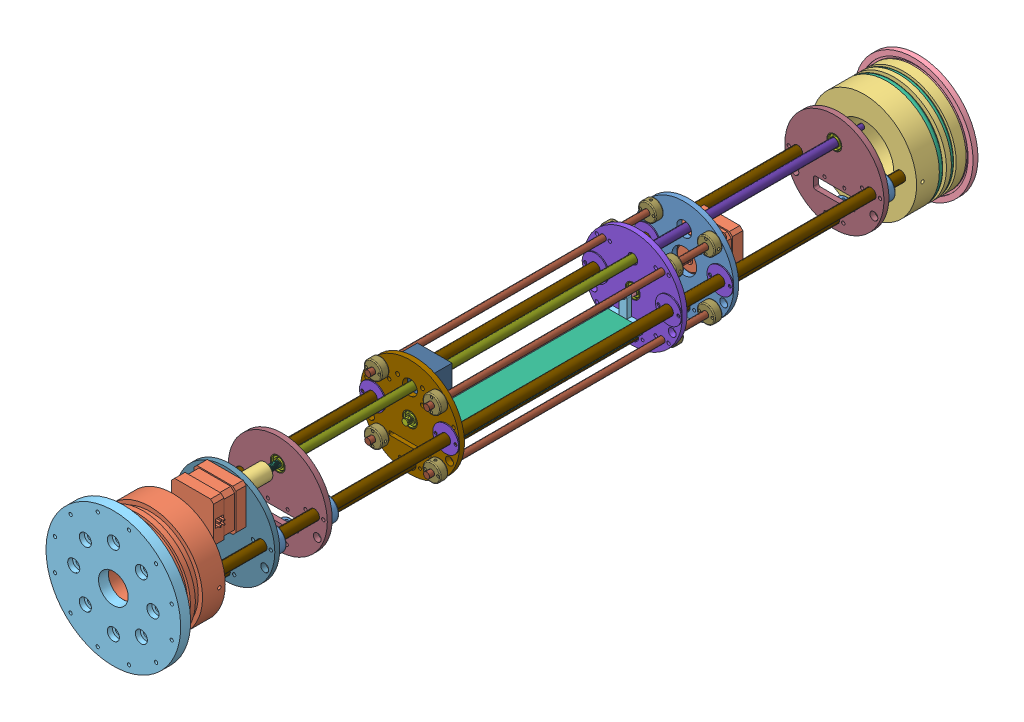
SolidWorks assembly MM_Main, configuration Default. Lengths in mm.
Overall size (192.33 192.33 813).
66 component instances, 27 part files, 135 mates.
Components (placement in the parent):
- MM_moving_stepper_disk-1: MM_moving_stepper_disk [Default] at (0 0 -581.4) size (100 100 5)
- MM_NEMA_17-1: MM_NEMA_17 [Default] at (0 -2 -614.4) x (1 0 0) z (0 -1 0) size (45.3 55 42.3)
- MM_5x5coupler-1: MM_5x5coupler [Default] at (0 -2 -541.4) x (0.507474 0.861667 0) z (0 0 -1) size (16 16 26)
- MM_Mass_shaft2-1: MM_Mass_shaft2 [Default] at (0 -2 -549.4) x (0.265176 0.9642 0) z (0.9642 -0.265176 0) size (8 34 8)
- MM_Mass_handle-1: MM_Mass_handle [Default] at (0 -30 -519.4) size (30 32 5)
- MM_Mass-1: MM_Mass [Default] at (-15 -30 -519.4) size (30 10 200)
- MM_Mass_handle-2: MM_Mass_handle [Default] at (0 -30 -314.4) size (30 32 5)
- MM_Mass_shaft-2: MM_Mass_shaft [Default] at (0 -2 -309.4) x (-0.93094 -0.365173 0) z (-0.365173 0.93094 0) size (9.17 19 8.51)
- MM_moving_disk-1: MM_moving_disk [Default] at (0 0 -529.4) size (100 100 5)
- MM_moving_disk2-1: MM_moving_disk2 [Default] at (0 0 -304.5) size (100 100 5)
- MM_shft_screw_nut-1: MM_shft_screw_nut [Default] at (0 26 -304.5) x (-1 0 0) z (0 -1 0) size (35 20 30)
- MM_moving_construct-1: MM_moving_construct [Default] at (-29.6985 29.6985 -586.5) x (-0.109158 -0.994024 0) z (0 0 1) size (6 6 300)
- MM_moving_construct-2: MM_moving_construct [Default] at (-29.6985 -29.6985 -586.5) x (0.994024 -0.109158 0) z (0 0 1) size (6 6 300)
- MM_moving_construct-3: MM_moving_construct [Default] at (29.6985 -29.6985 -586.5) x (0.109158 0.994024 0) z (0 0 1) size (6 6 300)
- MM_moving_construct-4: MM_moving_construct [Default] at (29.6985 29.6985 -586.5) x (-0.994024 0.109158 0) z (0 0 1) size (6 6 300)
- MM_moving_fix_thread-1: MM_moving_fix_thread [Default] at (29.6985 29.6985 -576.4) x (0 -1 0) z (0 0 1) size (18 18 8)
- MM_moving_fix_thread-2: MM_moving_fix_thread [Default] at (29.6985 29.6985 -537.4) x (0 -1 0) z (0 0 1) size (18 18 8)
- MM_moving_fix_thread-3: MM_moving_fix_thread [Default] at (29.6985 29.6985 -299.5) x (0 1 0) z (0 0 1) size (18 18 8)
- MM_moving_fix_thread-4: MM_moving_fix_thread [Default] at (29.6985 -29.6985 -576.4) x (-1 0 0) z (0 0 1) size (18 18 8)
- MM_moving_fix_thread-5: MM_moving_fix_thread [Default] at (-29.6985 -29.6985 -576.4) x (0 1 0) z (0 0 1) size (18 18 8)
- MM_moving_fix_thread-6: MM_moving_fix_thread [Default] at (-29.6985 29.6985 -576.4) size (18 18 8)
- MM_moving_fix_thread-7: MM_moving_fix_thread [Default] at (29.6985 -29.6985 -537.4) x (-1 0 0) z (0 0 1) size (18 18 8)
- MM_moving_fix_thread-8: MM_moving_fix_thread [Default] at (-29.6985 -29.6985 -537.4) x (0 1 0) z (0 0 1) size (18 18 8)
- MM_moving_fix_thread-9: MM_moving_fix_thread [Default] at (-29.6985 29.6985 -537.4) size (18 18 8)
- MM_moving_fix_thread-10: MM_moving_fix_thread [Default] at (29.6985 -29.6985 -299.5) size (18 18 8)
- MM_moving_fix_thread-11: MM_moving_fix_thread [Default] at (-29.6985 -29.6985 -299.5) x (0 -1 0) z (0 0 1) size (18 18 8)
- MM_moving_fix_thread-12: MM_moving_fix_thread [Default] at (-29.6985 29.6985 -299.5) x (-1 0 0) z (0 0 1) size (18 18 8)
- MM_static2.2-1: MM_static2.2 [Default] at (0 0 -171) size (100 100 5)
- MM_static_stepper-1: MM_static_stepper [Default] at (0 0 -118) size (100 100 5)
- MM_NEMA_17-2: MM_NEMA_17 [Default] at (0 26 -80) x (-1 0 0) z (0 -1 0) size (45.3 55 42.3)
- MM_5x5coupler-2: MM_5x5coupler [Default] at (0 26 -153) x (-0.062572 0.99804 0) z (0 0 1) size (16 16 26)
- MM_shaft_extend-2: MM_shaft_extend [Default] at (0 26 -145) x (-0.999277 -0.038026 0) z (0 0 -1) size (8 8 41)
- MM_shaft-2: MM_shaft [Default] at (0 26 -536) x (0.038026 -0.999277 0) z (0 0 1) size (8 8 360)
- MM_shaft_extend_long -1: MM_shaft_extend_long  [Default] at (0 26 -756) x (0.999277 0.038026 0) z (0 0 1) size (8 8 230)
- MM_static2.2-2: MM_static2.2 [Default] at (0 0 -733) size (100 100 5)
- MM_construct-1: MM_construct [Default] at (-37 0 -775.5) x (0.04747 0.998873 0) z (0 0 1) size (10 10 733)
- MM_fix-1: MM_fix [Default] at (-37 0 -179) x (0.99297 0.118365 0) z (0 0 1) size (24 24 8)
- MM_fix-2: MM_fix [Default] at (-37 0 -126) size (24 24 8)
- MM_fix-3: MM_fix [Default] at (-37 0 -741) size (24 24 8)
- MM_fix-4: MM_fix [Default] at (37 0 -733) x (-1 0 0) z (0 0 -1) size (24 24 8)
- MM_construct-2: MM_construct [Default] at (37 0 -42.5) x (-0.04747 0.998873 0) z (0 0 -1) size (10 10 733)
- MM_fix-5: MM_fix [Default] at (37 0 -171) x (-0.99297 0.118365 0) z (0 0 -1) size (24 24 8)
- MM_fix-6: MM_fix [Default] at (37 0 -118) x (-1 0 0) z (0 0 -1) size (24 24 8)
- MM_construct-3: MM_construct [Default] at (0 -40 -775.5) x (0.99877 -0.049577 0) z (0 0 1) size (10 10 733)
- MM_fix-7: MM_fix [Default] at (0 -40 -179) x (0.999988 0.004807 0) z (0 0 1) size (24 24 8)
- MM_fix-8: MM_fix [Default] at (0 -40 -126) x (0.999988 0.004807 0) z (0 0 1) size (24 24 8)
- MM_fix-9: MM_fix [Default] at (0 -40 -741) x (0.999988 0.004807 0) z (0 0 1) size (24 24 8)
- SE_mid_flange -1: SE_mid_flange  [Default] at (0 0 -10) x (-1 0 0) z (0 0 -1) size (106 106 50)
- SE_end_flange  - Copy-1: SE_end_flange  - Copy [Default] at (0 0 -808) size (106 106 50)
- SE_head3-1: SE_head3 [Default] at (0 0 -813) size (120 120 5)
- SE_cylinder-1: SE_cylinder [Default] at (0 0 -808) size (110.4 110.4 798) (hidden)
- SE_head2.2-1: SE_head2.2 [Default] at (0 0 -10) x (0.707107 -0.707107 0) z (0 0 1) size (136 136 10)
- o-rings ai-1: o-rings ai [AS568 - 241] at (0 0 -794.9393) x (1 0 0) z (0 -1 0) size (105.08 3.53 105.08)
- o-rings ai-2: o-rings ai [AS568 - 343] at (0 0 -783.6274) x (1 0 0) z (0 1 0) size (105.28 5.33 105.28)
- o-rings ai-3: o-rings ai [AS568 - 224] at (0 0 -807.0983) x (-1 0 0) z (0 -1 0) size (51.1 3.53 51.1)
- o-rings ai-7: o-rings ai [AS568 - 045] at (0 0 -808.5588) x (1 0 0) z (0 1 0) size (104.37 1.52 104.37)
- angular contact ball bearing_68_iso-1: angular contact ball bearing_68_iso [ISO 15 ABB - 196 - 10,SI,NC,10_68] at (0 -2 -302) x (0 0 -1) z (1 0 0) size (5 15 15)
- angular contact ball bearing_68_iso-2: angular contact ball bearing_68_iso [ISO 15 ABB - 196 - 10,SI,NC,10_68] at (0 26 -168.5) x (0 0 -1) z (1 0 0) size (5 15 15)
- angular contact ball bearing_68_iso-3: angular contact ball bearing_68_iso [ISO 15 ABB - 196 - 10,SI,NC,10_68] at (0 26 -730.5) x (0 0 -1) z (1 0 0) size (5 15 15)
- angular contact ball bearing_68_iso-4: angular contact ball bearing_68_iso [ISO 15 ABB - 196 - 10,SI,NC,10_68] at (0 -2 -526.9) x (0 0 -1) z (1 0 0) size (5 15 15)
- MM_smooth-1: MM_smooth [Default] at (-37 0 -581.4) size (26 26 6)
- MM_smooth-2: MM_smooth [Default] at (37 0 -581.4) size (26 26 6)
- MM_smooth-4: MM_smooth [Default] at (37 0 -529.4) size (26 26 6)
- MM_smooth-6: MM_smooth [Default] at (-37 0 -529.4) size (26 26 6)
- MM_smooth-8: MM_smooth [Default] at (37 0 -304.5) size (26 26 6)
- MM_smooth-9: MM_smooth [Default] at (-37 0 -304.5) size (26 26 6)
Mates (geometry in assembly coordinates):
- Concentric1: concentric anti-aligned: cylinder of MM_moving_stepper_disk-1 through (0 -2 -586.4) axis (0 0 1) radius 12.5; cylinder of MM_NEMA_17-1 through (0 -2 -559.4) axis (0 0 -1) radius 2.5
- Concentric2: concentric aligned: cylinder of MM_moving_stepper_disk-1 through (15.5 13.5 -586.4) axis (0 0 1) radius 2; cylinder of MM_NEMA_17-1 through (15.5 13.5 -585.9) axis (0 0 1) radius 1.5
- Coincident1: coincident anti-aligned: plane of MM_moving_stepper_disk-1 through (0 0 -581.4) normal (0 0 -1); plane of MM_NEMA_17-1 through (0 -2 -581.4) normal (0 0 1)
- Concentric3: concentric anti-aligned: cylinder of MM_NEMA_17-1 through (0 -2 -559.4) axis (0 0 -1) radius 2.5; cylinder of MM_5x5coupler-1 through (0 -2 -567.4) axis (0 0 1) radius 2.5
- Coincident3: coincident anti-aligned: plane of MM_NEMA_17-1 through (0 -2 -559.4) normal (0 0 1); circle of MM_5x5coupler-1
- Concentric7: concentric anti-aligned: cylinder of MM_5x5coupler-1 through (0 -2 -567.4) axis (0 0 1) radius 2.5; cylinder of MM_Mass_shaft2-1 through (0 -2 -534.4) axis (0 0 -1) radius 2.5
- Coincident5: coincident aligned: circle of MM_5x5coupler-1; plane of MM_Mass_shaft2-1 through (0 -2 -549.4) normal (0 0 -1)
- Concentric9: concentric aligned: cylinder of MM_Mass_shaft2-1 through (0 -2 -519.4) axis (0 0 -1) radius 4; cylinder of MM_Mass_handle-1 through (0 -2 -514.4) axis (0 0 -1) radius 4
- Coincident7: coincident anti-aligned: plane of MM_Mass_shaft2-1 through (0 -2 -519.4) normal (0 0 1); plane of MM_Mass_handle-1 through (0 -2 -519.4) normal (0 0 -1)
- Coincident8: coincident anti-aligned: plane of MM_Mass_handle-1 through (0 -2 -514.4) normal (0 0 1); plane of MM_Mass-1 through (15 -30 -514.4) normal (0 0 -1)
- Coincident9: coincident aligned: plane of MM_Mass_handle-1 through (-15 -30 -514.4) normal (-1 0 0); plane of MM_Mass-1 through (-15 -30 -309.4) normal (-1 0 0)
- Coincident10: coincident aligned: plane of MM_Mass_handle-1 through (15 -30 -514.4) normal (0 -1 0); plane of MM_Mass-1 through (-15 -30 -309.4) normal (0 -1 0)
- Coincident11: coincident aligned: plane of MM_Mass-1 through (15 -30 -309.4) normal (1 0 0); plane of MM_Mass_handle-2 through (15 -20 -309.4) normal (1 0 0)
- Coincident12: coincident anti-aligned: plane of MM_Mass-1 through (15 -30 -314.4) normal (0 0 1); plane of MM_Mass_handle-2 through (0 -2 -314.4) normal (0 0 -1)
- Coincident13: coincident aligned: plane of MM_Mass-1 through (-15 -30 -309.4) normal (0 -1 0); plane of MM_Mass_handle-2 through (15 -30 -309.4) normal (0 -1 0)
- Concentric10: concentric aligned: cylinder of MM_Mass_handle-2 through (0 -2 -309.4) axis (0 0 -1) radius 4; cylinder of MM_Mass_shaft-2 through (0 -2 -294.4) axis (0 0 -1) radius 4
- Coincident14: coincident anti-aligned: plane of MM_Mass_handle-2 through (0 -2 -309.4) normal (0 0 1); plane of MM_Mass_shaft-2 through (0 -2 -309.4) normal (0 0 -1)
- Concentric11: concentric aligned: cylinder of MM_moving_stepper_disk-1 through (0 0 -576.4) axis (0 0 -1) radius 50; cylinder of MM_moving_disk-1 through (0 0 -524.4) axis (0 0 -1) radius 50
- Concentric12: concentric aligned: cylinder of MM_moving_stepper_disk-1 through (37 0 -581.4) axis (0 0 -1) radius 7; cylinder of MM_moving_disk-1 through (37 0 -529.4) axis (0 0 -1) radius 7
- Coincident15: coincident anti-aligned: plane of MM_Mass_shaft2-1 through (0 -2 -524.4) normal (0 0 -1); plane of MM_moving_disk-1 through (0 0 -524.4) normal (0 0 1)
- Concentric13: concentric aligned: cylinder of MM_moving_disk-1 through (0 0 -524.4) axis (0 0 -1) radius 50; cylinder of MM_moving_disk2-1 through (0 0 -299.5) axis (0 0 -1) radius 50
- Concentric14: concentric aligned: cylinder of MM_moving_disk-1 through (37 0 -529.4) axis (0 0 -1) radius 7; cylinder of MM_moving_disk2-1 through (37 0 -304.5) axis (0 0 -1) radius 7
- Coincident16: coincident anti-aligned: plane of MM_Mass_shaft-2 through (0 -2 -304.5) normal (0 0 1); plane of MM_moving_disk2-1 through (0 0 -304.5) normal (0 0 -1)
- Concentric15: concentric aligned: cylinder of MM_moving_disk2-1 through (0 26 -309.5) axis (0 0 1) radius 7.5; cylinder of MM_shft_screw_nut-1 through (0 26 -324.5) axis (0 0 1) radius 8.5
- Concentric16: concentric aligned: cylinder of MM_moving_disk2-1 through (12.5 31.5 -309.5) axis (0 0 1) radius 2; cylinder of MM_shft_screw_nut-1 through (12.5 31.5 -304.5) axis (0 0 1) radius 1.25
- Coincident17: coincident anti-aligned: plane of MM_moving_disk2-1 through (0 0 -304.5) normal (0 0 -1); plane of MM_shft_screw_nut-1 through (0 26 -304.5) normal (0 0 1)
- Concentric17: concentric anti-aligned: cylinder of MM_moving_disk2-1 through (-29.6985 29.6985 -309.5) axis (0 0 1) radius 3; cylinder of MM_moving_construct-1 through (-29.6985 29.6985 -286.5) axis (0 0 -1) radius 3
- Coincident27: coincident anti-aligned: circle of MM_moving_stepper_disk-1; cylinder of MM_moving_fix_thread-1 through (29.6985 29.6985 -576.4) axis (0 0 -1) radius 3
- Coincident28: coincident anti-aligned: plane of MM_moving_stepper_disk-1 through (0 0 -576.4) normal (0 0 1); plane of MM_moving_fix_thread-1 through (29.6985 29.6985 -576.4) normal (0 0 -1)
- Coincident30: coincident anti-aligned: circle of MM_moving_disk-1; cylinder of MM_moving_fix_thread-2 through (29.6985 29.6985 -537.4) axis (0 0 -1) radius 3
- Coincident31: coincident anti-aligned: plane of MM_moving_fix_thread-2 through (29.6985 29.6985 -529.4) normal (0 0 1); plane of MM_moving_disk-1 through (0 0 -529.4) normal (0 0 -1)
- Coincident33: coincident anti-aligned: circle of MM_moving_disk2-1; cylinder of MM_moving_fix_thread-3 through (29.6985 29.6985 -299.5) axis (0 0 -1) radius 3
- Coincident34: coincident anti-aligned: plane of MM_moving_disk2-1 through (0 0 -299.5) normal (0 0 1); plane of MM_moving_fix_thread-3 through (29.6985 29.6985 -299.5) normal (0 0 -1)
- Concentric18: concentric aligned: cylinder of MM_moving_disk2-1 through (0 0 -299.5) axis (0 0 -1) radius 50; cylinder of MM_static2.2-1 through (0 0 -166) axis (0 0 -1) radius 50
- Concentric19: concentric aligned: cylinder of MM_moving_disk2-1 through (-37 0 -304.5) axis (0 0 -1) radius 7; cylinder of MM_static2.2-1 through (-37 0 -171) axis (0 0 -1) radius 5.1
- Concentric20: concentric aligned: cylinder of MM_static2.2-1 through (0 0 -166) axis (0 0 -1) radius 50; cylinder of MM_static_stepper-1 through (0 0 -113) axis (0 0 -1) radius 50
- Concentric21: concentric aligned: cylinder of MM_static2.2-1 through (0 26 -176) axis (0 0 1) radius 7.5; cylinder of MM_static_stepper-1 through (0 26 -123) axis (0 0 1) radius 12.5
- Concentric22: concentric aligned: cylinder of MM_static_stepper-1 through (0 26 -123) axis (0 0 1) radius 12.5; cylinder of MM_NEMA_17-2 through (0 26 -135) axis (0 0 1) radius 2.5
- Parallel6: parallel aligned: plane of MM_NEMA_17-2 through (-16 46 -90.5) normal (0 1 0); plane of assembly through (0 0 0) normal (0 1 0)
- Coincident37: coincident anti-aligned: plane of MM_static_stepper-1 through (0 0 -113) normal (0 0 1); plane of MM_NEMA_17-2 through (0 26 -113) normal (0 0 -1)
- Coincident38: coincident anti-aligned: plane of MM_NEMA_17-2 through (0 26 -135) normal (0 0 -1); circle of MM_5x5coupler-2
- Concentric23: concentric anti-aligned: cylinder of MM_NEMA_17-2 through (0 26 -135) axis (0 0 1) radius 2.5; cylinder of MM_5x5coupler-2 through (0 26 -127) axis (0 0 -1) radius 2.5
- Coincident39: coincident aligned: circle of MM_5x5coupler-2; plane of MM_shaft_extend-2 through (0 26 -145) normal (0 0 1)
- Concentric24: concentric anti-aligned: cylinder of MM_5x5coupler-2 through (0 26 -127) axis (0 0 -1) radius 2.5; cylinder of MM_shaft_extend-2 through (0 26 -155) axis (0 0 1) radius 2.5
- Coincident40: coincident anti-aligned: plane of MM_static2.2-1 through (0 0 -171) normal (0 0 -1); plane of MM_shaft_extend-2 through (0 26 -171) normal (0 0 1)
- Concentric25: concentric anti-aligned: cylinder of MM_shft_screw_nut-1 through (0 26 -324.5) axis (0 0 1) radius 8.5; cylinder of MM_shaft-2 through (0 26 -186) axis (0 0 -1) radius 4
- Coincident41: coincident anti-aligned: plane of MM_shaft_extend-2 through (0 26 -176) normal (0 0 -1); plane of MM_shaft-2 through (0 26 -176) normal (0 0 1)
- Concentric26: concentric anti-aligned: cylinder of MM_shaft_extend-2 through (-9.9928 25.6197 -181) axis (0.999277 0.038026 0) radius 1; cylinder of MM_shaft-2 through (2.9978 26.1141 -181) axis (-0.999277 -0.038026 0) radius 1
- Distance1: distance = 5 mm aligned: plane of MM_moving_construct-3 through (29.6985 -29.6985 -286.5) normal (0 0 1); plane of MM_moving_fix_thread-10 through (29.6985 -29.6985 -291.5) normal (0 0 1)
- Concentric27: concentric anti-aligned: cylinder of MM_shaft-2 through (0 26 -526) axis (0 0 -1) radius 3; cylinder of MM_shaft_extend_long -1 through (0 26 -536) axis (0 0 1) radius 3
- Concentric28: concentric anti-aligned: cylinder of MM_shaft-2 through (-3.9971 25.8479 -531) axis (0.999277 0.038026 0) radius 1; cylinder of MM_shaft_extend_long -1 through (9.9928 26.3803 -531) axis (-0.999277 -0.038026 0) radius 1
- Concentric29: concentric aligned: cylinder of MM_static2.2-1 through (0 0 -166) axis (0 0 -1) radius 50; cylinder of MM_static2.2-2 through (0 0 -728) axis (0 0 -1) radius 50
- Concentric30: concentric anti-aligned: cylinder of MM_shaft_extend_long -1 through (0 26 -526) axis (0 0 -1) radius 4; cylinder of MM_static2.2-2 through (0 26 -738) axis (0 0 1) radius 7.5
- Coincident44: coincident anti-aligned: plane of MM_shaft_extend_long -1 through (0 26 -728) normal (0 0 -1); plane of MM_static2.2-2 through (0 0 -728) normal (0 0 1)
- LimitDistance1: limit distance = 128.5 mm anti-aligned: plane of MM_moving_disk2-1 through (0 0 -299.5) normal (0 0 1); plane of MM_static2.2-1 through (0 0 -171) normal (0 0 -1)
- Concentric31: concentric aligned: cylinder of MM_static_stepper-1 through (-37 0 -118) axis (0 0 -1) radius 5.1; cylinder of MM_construct-1 through (-37 0 -42.5) axis (0 0 -1) radius 5
- Concentric32: concentric aligned: cylinder of MM_fix-1 through (-37 0 -179) axis (0 0 -1) radius 5.1; circle of MM_static2.2-1
- Coincident47: coincident anti-aligned: plane of MM_static2.2-1 through (0 0 -171) normal (0 0 -1); plane of MM_fix-1 through (-37 0 -171) normal (0 0 1)
- Coincident52: coincident aligned: circle of MM_static_stepper-1; cylinder of MM_fix-2 through (-37 0 -126) axis (0 0 -1) radius 5.1
- Coincident53: coincident anti-aligned: plane of MM_static_stepper-1 through (0 0 -118) normal (0 0 -1); plane of MM_fix-2 through (-37 0 -118) normal (0 0 1)
- Coincident59: coincident aligned: circle of MM_static2.2-2; cylinder of MM_fix-3 through (-37 0 -741) axis (0 0 -1) radius 5.1
- Coincident60: coincident anti-aligned: plane of MM_static2.2-2 through (0 0 -733) normal (0 0 -1); plane of MM_fix-3 through (-37 0 -733) normal (0 0 1)
- Coincident77: coincident anti-aligned: plane of MM_static_stepper-1 through (0 0 -118) normal (0 0 -1); plane of MM_fix-8 through (0 -40 -118) normal (0 0 1)
- Coincident79: coincident anti-aligned: plane of MM_static2.2-1 through (0 0 -171) normal (0 0 -1); plane of MM_fix-7 through (0 -40 -171) normal (0 0 1)
- Coincident81: coincident anti-aligned: plane of MM_static2.2-2 through (0 0 -733) normal (0 0 -1); plane of MM_fix-9 through (0 -40 -733) normal (0 0 1)
- Concentric40: concentric aligned: cylinder of MM_construct-3 through (0 -40 -42.5) axis (0 0 -1) radius 5; cylinder of MM_fix-9 through (0 -40 -741) axis (0 0 -1) radius 5.1
- Coincident82: coincident aligned: plane of MM_construct-1 through (-37 0 -775.5) normal (0 0 -1); plane of MM_construct-3 through (0 -40 -775.5) normal (0 0 -1)
- Concentric41: concentric anti-aligned: cylinder of MM_static_stepper-1 through (0 0 -113) axis (0 0 -1) radius 50; cylinder of SE_mid_flange -1 through (0 0 -60) axis (0 0 1) radius 53
- Distance2: distance = 20 mm anti-aligned: plane of SE_mid_flange -1 through (0 0 -60) normal (0 0 -1); plane of MM_NEMA_17-2 through (0 26 -80) normal (0 0 1)
- Coincident84: coincident anti-aligned: plane of MM_construct-1 through (-37 0 -42.5) normal (0 0 1); circle of SE_mid_flange -1
- Concentric46: concentric aligned: cylinder of MM_static2.2-2 through (0 0 -728) axis (0 0 -1) radius 50; cylinder of SE_end_flange  - Copy-1 through (0 0 -758) axis (0 0 -1) radius 53
- Concentric47: concentric anti-aligned: circle of MM_fix-3; cylinder of SE_end_flange  - Copy-1 through (-37 0 -758) axis (0 0 1) radius 5
- Concentric48: concentric anti-aligned: cylinder of SE_end_flange  - Copy-1 through (0 0 -758) axis (0 0 -1) radius 53; cylinder of SE_head3-1 through (0 0 -813) axis (0 0 1) radius 60
- Concentric49: concentric anti-aligned: cylinder of SE_end_flange  - Copy-1 through (-28.2843 28.2843 -808) axis (0 0 -1) radius 2.1; cylinder of SE_head3-1 through (-28.2843 28.2843 -813) axis (0 0 1) radius 3
- Coincident88: coincident anti-aligned: plane of SE_end_flange  - Copy-1 through (0 0 -808) normal (0 0 -1); plane of SE_head3-1 through (0 0 -808) normal (0 0 1)
- Concentric50: concentric aligned: cylinder of SE_end_flange  - Copy-1 through (0 0 -758) axis (0 0 -1) radius 53; cylinder of SE_cylinder-1 through (0 0 -10) axis (0 0 -1) radius 53
- Coincident89: coincident anti-aligned: plane of SE_head3-1 through (0 0 -808) normal (0 0 1); plane of SE_cylinder-1 through (0 0 -808) normal (0 0 -1)
- Coincident92: coincident aligned: plane of SE_cylinder-1 through (0 0 -808) normal (1 0 0); plane of assembly through (0 0 0) normal (1 0 0)
- Coincident93: coincident aligned: plane of SE_cylinder-1 through (0 0 -808) normal (0 1 0); plane of assembly through (0 0 0) normal (0 1 0)
- Parallel8: parallel aligned: plane of MM_NEMA_17-2 through (-16 46 -90.5) normal (0 1 0); plane of assembly through (0 0 0) normal (0 1 0)
- Concentric51: concentric anti-aligned: circle of MM_static_stepper-1; cylinder of MM_NEMA_17-2 through (-15.5 41.5 -108.5) axis (0 0 -1) radius 1.5
- LimitAngle2: limit planar angle = 1.570796 rad anti-aligned: plane of MM_Mass_handle-1 through (-4 -2 -514.4) normal (-1 0 0); plane of assembly through (0 0 0) normal (0 1 0)
- Concentric52: concentric aligned: cylinder of SE_mid_flange -1 through (0 0 -60) axis (0 0 1) radius 53; cylinder of SE_head2.2-1 through (0 0 -10) axis (0 0 1) radius 68
- Concentric53: concentric aligned: cylinder of SE_mid_flange -1 through (0 -40 -10) axis (0 0 1) radius 2.1; cylinder of SE_head2.2-1 through (0 -40 0) axis (0 0 1) radius 2.75
- Coincident94: coincident anti-aligned: plane of SE_mid_flange -1 through (0 0 -10) normal (0 0 1); plane of SE_head2.2-1 through (0 0 -10) normal (0 0 -1)
- Coincident95: coincident: plane of SE_head2.2-1 through (0 0 0) normal (0 0 1)
- Coincident96: coincident anti-aligned: plane of MM_construct-1 through (-37 0 -775.5) normal (0 0 -1); circle of SE_end_flange  - Copy-1
- Parallel9: parallel aligned: plane of o-rings ai-1 through (0 0 -794.9393) normal (0 0 1); plane of assembly through (0 0 0) normal (0 0 1)
- Coincident98: coincident aligned: plane of o-rings ai-1 through (0 0 -794.9393) normal (1 0 0); plane of assembly through (0 0 0) normal (1 0 0)
- Coincident99: coincident anti-aligned: plane of o-rings ai-1 through (0 0 -794.9393) normal (0 -1 0); plane of assembly through (0 0 0) normal (0 1 0)
- Tangent1: tangent: torus of o-rings ai-1; plane of SE_end_flange  - Copy-1 through (0 53 -793.174) normal (0 0 -1)
- Parallel10: parallel anti-aligned: plane of o-rings ai-2 through (0 0 -783.6274) normal (0 0 -1); plane of assembly through (0 0 0) normal (0 0 1)
- Coincident101: coincident aligned: plane of o-rings ai-2 through (0 0 -783.6274) normal (0 1 0); plane of assembly through (0 0 0) normal (0 1 0)
- Coincident102: coincident aligned: plane of o-rings ai-2 through (0 0 -783.6274) normal (1 0 0); plane of assembly through (0 0 0) normal (1 0 0)
- Tangent2: tangent: plane of SE_end_flange  - Copy-1 through (0 53 -780.9604) normal (0 0 -1); torus of o-rings ai-2
- Parallel11: parallel anti-aligned: plane of o-rings ai-7 through (0 0 -808.5588) normal (0 0 -1); plane of assembly through (0 0 0) normal (0 0 1)
- Coincident104: coincident aligned: plane of o-rings ai-7 through (0 0 -808.5588) normal (0 1 0); plane of assembly through (0 0 0) normal (0 1 0)
- Coincident105: coincident aligned: plane of o-rings ai-7 through (0 0 -808.5588) normal (1 0 0); plane of assembly through (0 0 0) normal (1 0 0)
- Tangent3: tangent: plane of SE_head3-1 through (0 0 -809.3208) normal (0 0 1); torus of o-rings ai-7
- Parallel12: parallel anti-aligned: plane of o-rings ai-3 through (0 0 -807.0983) normal (0 0 -1); plane of assembly through (0 0 0) normal (0 0 1)
- Coincident107: coincident anti-aligned: plane of o-rings ai-3 through (0 0 -807.0983) normal (0 -1 0); plane of assembly through (0 0 0) normal (0 1 0)
- Coincident108: coincident anti-aligned: plane of o-rings ai-3 through (0 0 -807.0983) normal (-1 0 0); plane of assembly through (0 0 0) normal (1 0 0)
- Tangent4: tangent: plane of SE_end_flange  - Copy-1 through (0 27.1526 -805.333) normal (0 0 -1); torus of o-rings ai-3
- Concentric54: concentric anti-aligned: cylinder of MM_moving_disk2-1 through (0 -2 -309.5) axis (0 0 1) radius 7.5; cylinder of angular contact ball bearing_68_iso-1 through (0 -2 -281.3625) axis (0 0 -1) radius 3
- Coincident109: coincident aligned: plane of MM_moving_disk2-1 through (0 0 -299.5) normal (0 0 1); plane of angular contact ball bearing_68_iso-1 through (0 4.575 -299.5) normal (0 0 1)
- Concentric55: concentric anti-aligned: cylinder of MM_static2.2-2 through (0 26 -738) axis (0 0 1) radius 7.5; cylinder of angular contact ball bearing_68_iso-3 through (0 26 -709.8625) axis (0 0 -1) radius 3
- Coincident110: coincident anti-aligned: plane of MM_static2.2-2 through (0 0 -728) normal (0 0 1); circle of angular contact ball bearing_68_iso-3
- Concentric56: concentric anti-aligned: cylinder of MM_static2.2-1 through (0 26 -176) axis (0 0 1) radius 7.5; cylinder of angular contact ball bearing_68_iso-2 through (0 26 -147.8625) axis (0 0 -1) radius 3
- Coincident111: coincident aligned: plane of MM_static2.2-1 through (0 0 -171) normal (0 0 -1); plane of angular contact ball bearing_68_iso-2 through (0 33.3 -171) normal (0 0 -1)
- Concentric57: concentric anti-aligned: cylinder of MM_moving_disk-1 through (0 -2 -534.4) axis (0 0 1) radius 7.5; cylinder of angular contact ball bearing_68_iso-4 through (0 -2 -506.2625) axis (0 0 -1) radius 3
- Coincident112: coincident aligned: plane of MM_moving_disk-1 through (0 0 -524.4) normal (0 0 1); plane of angular contact ball bearing_68_iso-4 through (0 4.575 -524.4) normal (0 0 1)
- Concentric58: concentric aligned: cylinder of MM_Mass_handle-1 through (11 -25 -519.4) axis (0 0 -1) radius 1.7; cylinder of MM_Mass-1 through (11 -25 -514.4) axis (0 0 -1) radius 1.25
- Concentric59: concentric anti-aligned: cylinder of MM_Mass_handle-2 through (0 -2 -309.4) axis (0 0 -1) radius 4; circle of MM_moving_disk2-1
- Concentric60: concentric anti-aligned: cylinder of MM_construct-2 through (37 0 -775.5) axis (0 0 1) radius 5; circle of SE_mid_flange -1
- Concentric61: concentric aligned: cylinder of MM_moving_stepper_disk-1 through (-37 0 -581.4) axis (0 0 -1) radius 7; cylinder of MM_smooth-1 through (-37 0 -575.4) axis (0 0 -1) radius 5
- Concentric63: concentric anti-aligned: cylinder of MM_moving_stepper_disk-1 through (37 0 -581.4) axis (0 0 -1) radius 7; circle of MM_smooth-2
- Concentric64: concentric aligned: cylinder of MM_moving_disk-1 through (-37 0 -529.4) axis (0 0 -1) radius 7; cylinder of MM_smooth-6 through (-37 0 -523.4) axis (0 0 -1) radius 5
- Concentric66: concentric aligned: cylinder of MM_moving_disk-1 through (37 0 -529.4) axis (0 0 -1) radius 7; cylinder of MM_smooth-4 through (37 0 -523.4) axis (0 0 -1) radius 5
- Concentric67: concentric aligned: cylinder of MM_moving_disk2-1 through (-37 0 -304.5) axis (0 0 -1) radius 7; cylinder of MM_smooth-9 through (-37 0 -298.5) axis (0 0 -1) radius 5
- Concentric68: concentric aligned: cylinder of MM_moving_disk2-1 through (37 0 -304.5) axis (0 0 -1) radius 7; cylinder of MM_smooth-8 through (37 0 -298.5) axis (0 0 -1) radius 5
- Coincident114: coincident aligned: plane of MM_moving_stepper_disk-1 through (0 0 -581.4) normal (0 0 -1); plane of MM_smooth-1 through (-37 0 -581.4) normal (0 0 -1)
- Coincident115: coincident aligned: plane of MM_moving_disk-1 through (0 0 -529.4) normal (0 0 -1); plane of MM_smooth-6 through (-37 0 -529.4) normal (0 0 -1)
- Coincident116: coincident aligned: plane of MM_moving_disk2-1 through (0 0 -304.5) normal (0 0 -1); plane of MM_smooth-9 through (-37 0 -304.5) normal (0 0 -1)
- Coincident117: coincident aligned: plane of MM_moving_disk2-1 through (0 0 -304.5) normal (0 0 -1); plane of MM_smooth-8 through (37 0 -304.5) normal (0 0 -1)
- Coincident118: coincident aligned: plane of MM_moving_stepper_disk-1 through (0 0 -581.4) normal (0 0 -1); plane of MM_smooth-2 through (37 0 -581.4) normal (0 0 -1)
- Coincident119: coincident aligned: plane of MM_moving_disk-1 through (0 0 -529.4) normal (0 0 -1); plane of MM_smooth-4 through (37 0 -529.4) normal (0 0 -1)
- Concentric69: concentric aligned: cylinder of MM_moving_disk-1 through (47 0 -534.4) axis (0 0 1) radius 1.5; cylinder of MM_smooth-4 through (47 0 -524.4) axis (0 0 1) radius 1.5
- Concentric70: concentric aligned: cylinder of MM_moving_stepper_disk-1 through (47 0 -586.4) axis (0 0 1) radius 1.5; cylinder of MM_smooth-2 through (47 0 -576.4) axis (0 0 1) radius 1.5
- Concentric71: concentric aligned: cylinder of MM_moving_disk2-1 through (47 0 -309.5) axis (0 0 1) radius 1.5; cylinder of MM_smooth-8 through (47 0 -299.5) axis (0 0 1) radius 1.5
- Concentric72: concentric aligned: cylinder of MM_moving_disk2-1 through (-47 0 -309.5) axis (0 0 1) radius 1.5; cylinder of MM_smooth-9 through (-47 0 -299.5) axis (0 0 1) radius 1.5
- Concentric73: concentric aligned: cylinder of MM_moving_disk-1 through (-47 0 -534.4) axis (0 0 1) radius 1.5; cylinder of MM_smooth-6 through (-47 0 -524.4) axis (0 0 1) radius 1.5
- Concentric74: concentric aligned: cylinder of MM_moving_stepper_disk-1 through (-47 0 -586.4) axis (0 0 1) radius 1.5; cylinder of MM_smooth-1 through (-47 0 -576.4) axis (0 0 1) radius 1.5
- Concentric78: concentric aligned: cylinder of MM_moving_disk2-1 through (-36.1985 29.6985 -299.5) axis (0 0 1) radius 1.7; cylinder of MM_moving_fix_thread-12 through (-36.1985 29.6985 -291.5) axis (0 0 1) radius 1.25
- Concentric79: concentric aligned: cylinder of MM_moving_disk-1 through (-36.1985 29.6985 -524.4) axis (0 0 1) radius 1.7; cylinder of MM_moving_fix_thread-9 through (-36.1985 29.6985 -529.4) axis (0 0 1) radius 1.25
- Concentric80: concentric aligned: cylinder of MM_moving_stepper_disk-1 through (-36.1985 29.6985 -576.4) axis (0 0 1) radius 1.7; cylinder of MM_moving_fix_thread-6 through (-36.1985 29.6985 -568.4) axis (0 0 1) radius 1.25
